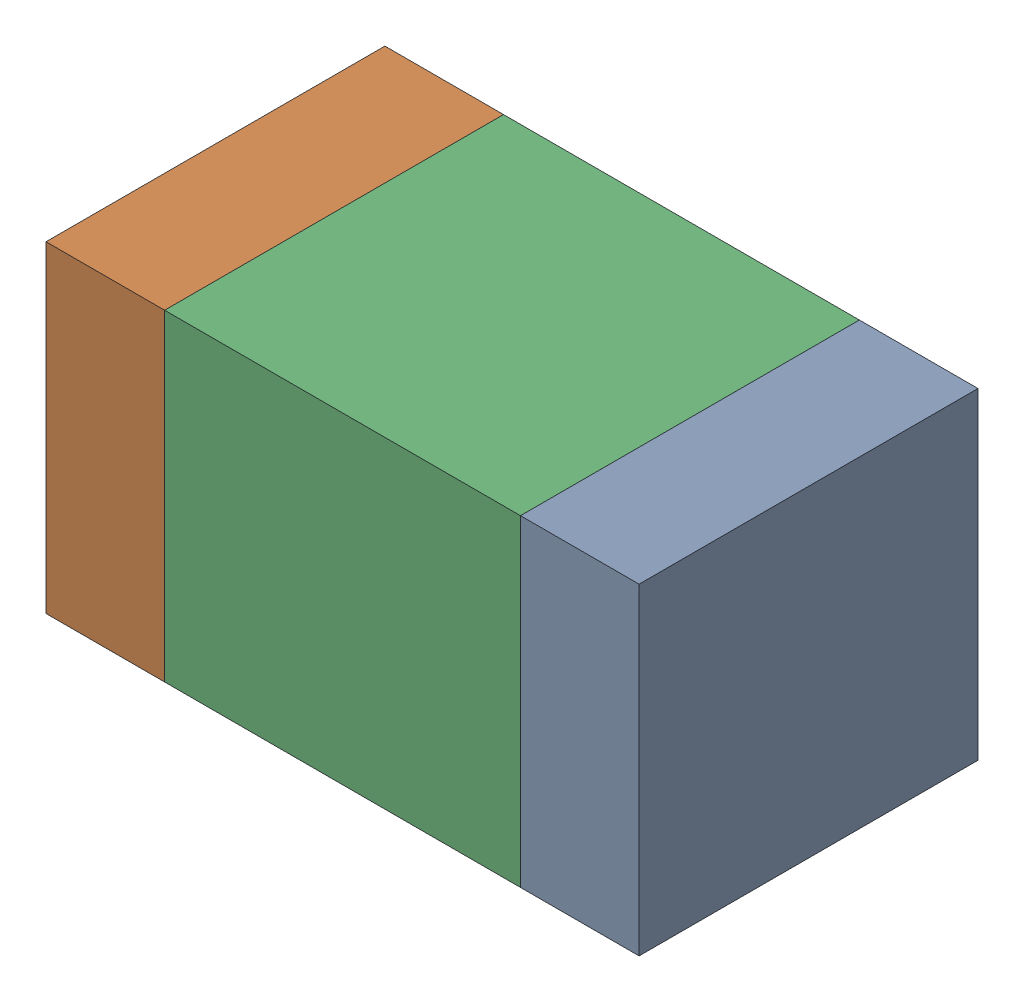
SolidWorks assembly C12-2, configuration Default. Lengths in mm.
Overall size (1.75 0.95 1).
6 component instances, 2 part files, 0 mates.
Components (placement in the parent):
- 959208936-2-1: 959208936-2 [Default] at (92.521 76.327 0) size (0.35 0.95 1)
  - Extruded-78-1: Extruded-78 [Default] at origin size (0.35 0.95 1)
- 959208936-2-2: 959208936-2 [Default] at (91.121 76.327 0) size (0.35 0.95 1)
  - Extruded-78-1: Extruded-78 [Default] at origin size (0.35 0.95 1)
- 959208800-2-1: 959208800-2 [Default] at (91.821 76.327 0) size (1.05 0.95 1)
  - Extruded-79-1: Extruded-79 [Default] at origin size (1.05 0.95 1)
